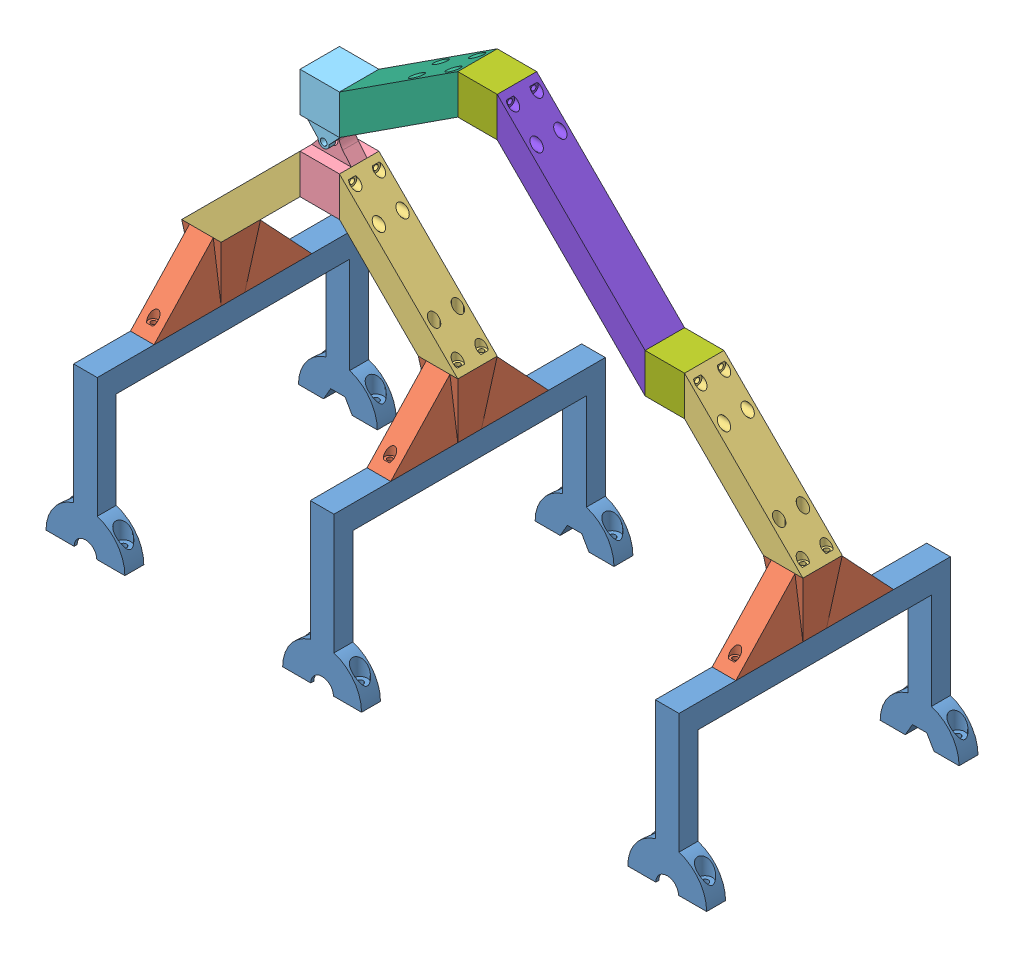
SolidWorks assembly Rocker_Bogie_1.0, configuration Default. Lengths in mm.
Overall size (418.71 308.71 172).
16 component instances, 8 part files, 24 mates.
Components (placement in the parent):
- Rocker_1.0-1: Rocker_1.0 [Default] at (-37.3231 -23.6095 57.3798) size (200 230 172)
  - foot_1.0-1: foot_1.0 [Default] at (23.1128 115.6532 136.1153) size (50 100 172)
  - foot_connect_1.0-1: foot_connect_1.0 [Default] at (23.1128 123.1532 136.1153) x (0 0 -1) z (1 0 0) size (100 40 25)
  - Rocker_Bar_1.0-1: Rocker_Bar_1.0 [Default] at (85.6128 213.1532 123.6153) x (0 0 1) z (-1 0 0) size (25 75 75)
  - Rocker_Pivot_1.0-1: Rocker_Pivot_1.0 [Default] at (98.1128 213.1532 136.1153) size (25 40 25)
  - Rocker_Bar_1.0-2: Rocker_Bar_1.0 [Default] at (160.6128 163.1532 123.6153) x (0 0 1) z (0 1 0) size (25 75 75)
  - foot_connect_1.0-2: foot_connect_1.0 [Default] at (173.1128 123.1532 136.1153) x (0.000001 0 -1) z (1 0 0.000001) size (100 40 25)
  - foot_1.0-2: foot_1.0 [Default] at (173.1128 115.6532 136.1153) x (1 0 0.000001) z (-0.000001 0 1) size (50 100 172)
- Rocker_Bogie_Connect_1.0-1: Rocker_Bogie_Connect_1.0 [Default] at (60.7897 247.0437 193.4951) x (0 1 0) z (1 0 0) size (38.5 25 25)
- Bogie_Bar_1.0-1: Bogie_Bar_1.0 [Default] at (148.2897 283.2492 180.9951) x (0 0 1) z (-1 0 0) size (25 73.71 75)
- Bogie_Connect_1.0-1: Bogie_Connect_1.0 [Default] at (160.7897 283.2492 193.4951) size (25 25 25)
- Bogie_Bar2_1.0-1: Bogie_Bar2_1.0 [Default] at (173.2897 283.2492 205.9951) x (0 0 -1) z (1 0 0) size (25 118.71 93.71)
- Bogie_Connect_1.0-2: Bogie_Connect_1.0 [Default] at (279.4996 189.5393 193.4951) size (25 25 25)
- Rocker_Bar_1.0-1: Rocker_Bar_1.0 [Default] at (291.9996 189.5393 205.9951) x (0 0 -1) z (1 0 0) size (25 75 75)
- foot_connect_1.0-1: foot_connect_1.0 [Default] at (354.4996 99.5393 193.4952) x (0 0 -1) z (1 0 0) size (100 40 25)
- foot_1.0-1: foot_1.0 [Default] at (354.4996 92.0393 193.4952) size (50 100 172)
Mates (geometry in assembly coordinates):
- Concentric1: concentric: cylinder of Rocker_1.0-1/Rocker_Pivot_1.0-1 through (60.7897 224.5437 198.4951) axis (0 0 -1) radius 4; cylinder of Rocker_Bogie_Connect_1.0-1 through (60.7897 224.5437 187.4951) axis (0 0 1) radius 2.5
- Coincident1: coincident: plane of Rocker_1.0-1/Rocker_Pivot_1.0-1 through (48.2897 214.5437 180.9951) normal (0 0 -1); plane of Rocker_Bogie_Connect_1.0-1 through (48.2897 234.5437 180.9951) normal (0 0 -1)
- Coincident3: coincident: plane of Rocker_Bogie_Connect_1.0-1 through (73.2897 247.0437 193.4951) normal (1 0 0); plane of Bogie_Bar_1.0-1 through (73.2897 234.5437 205.9951) normal (-1 0 0)
- Concentric2: concentric: cylinder of Rocker_Bogie_Connect_1.0-1 through (73.2897 239.5437 200.9951) axis (1 0 0) radius 2.5; circle of Bogie_Bar_1.0-1
- Concentric3: concentric: cylinder of Bogie_Bar_1.0-1 through (73.2887 303.2492 200.9951) axis (1 0 0) radius 1.6; cylinder of Bogie_Connect_1.0-1 through (148.2897 303.2492 200.9951) axis (-1 0 0) radius 2.5
- Coincident4: coincident: plane of Bogie_Bar_1.0-1 through (148.2897 283.2492 205.9951) normal (0 0 1); plane of Bogie_Connect_1.0-1 through (148.2897 308.2492 205.9951) normal (0 0 1)
- Coincident5: coincident: plane of Bogie_Bar_1.0-1 through (148.2897 308.2492 205.9951) normal (1 0 0); plane of Bogie_Connect_1.0-1 through (148.2897 308.2492 180.9951) normal (-1 0 0)
- Coincident6: coincident: plane of Rocker_Bogie_Connect_1.0-1 through (48.2897 234.5437 180.9951) normal (0 0 -1); plane of Bogie_Bar_1.0-1 through (148.2897 283.2492 180.9951) normal (0 0 -1)
- Parallel3: parallel: line of Rocker_1.0-1/Rocker_Pivot_1.0-1 through (48.2897 214.5437 205.9951) axis (1 0 0); line of Rocker_Bogie_Connect_1.0-1 through (48.2897 234.5437 205.9951) axis (1 0 0)
- Coincident12: coincident: plane of Bogie_Connect_1.0-1 through (173.2897 308.2492 180.9951) normal (1 0 0); plane of Bogie_Bar2_1.0-1 through (173.2897 308.2492 180.9951) normal (-1 0 0)
- Concentric5: concentric: cylinder of Bogie_Connect_1.0-1 through (173.2897 303.2492 185.9951) axis (1 0 0) radius 2.5; circle of Bogie_Bar2_1.0-1
- Coincident13: coincident: plane of Bogie_Connect_1.0-1 through (148.2897 308.2492 205.9951) normal (0 0 1); plane of Bogie_Bar2_1.0-1 through (173.2897 283.2492 205.9951) normal (0 0 1)
- Coincident14: coincident: plane of Bogie_Bar2_1.0-1 through (266.9996 189.5393 180.9951) normal (1 0 0); plane of Bogie_Connect_1.0-2 through (266.9996 214.5393 180.9951) normal (-1 0 0)
- Coincident15: coincident: plane of Bogie_Bar2_1.0-1 through (173.2897 283.2492 205.9951) normal (0 0 1); plane of Bogie_Connect_1.0-2 through (266.9996 214.5393 205.9951) normal (0 0 1)
- Concentric6: concentric: cylinder of Bogie_Bar2_1.0-1 through (173.2887 209.5393 200.9951) axis (1 0 0) radius 1.6; cylinder of Bogie_Connect_1.0-2 through (266.9996 209.5393 200.9951) axis (-1 0 0) radius 2.5
- Coincident16: coincident: plane of Bogie_Connect_1.0-2 through (266.9996 214.5393 205.9951) normal (0 0 1); plane of Rocker_Bar_1.0-1 through (291.9996 189.5393 205.9951) normal (0 0 1)
- Coincident17: coincident: plane of Bogie_Connect_1.0-2 through (291.9996 214.5393 180.9951) normal (1 0 0); plane of Rocker_Bar_1.0-1 through (291.9996 214.5393 180.9951) normal (-1 0 0)
- Concentric7: concentric: cylinder of Bogie_Connect_1.0-2 through (291.9996 209.5393 185.9951) axis (1 0 0) radius 2.5; circle of Rocker_Bar_1.0-1
- Coincident18: coincident: plane of Rocker_Bar_1.0-1 through (341.9996 139.5393 180.9951) normal (0 -1 0); plane of foot_connect_1.0-1 through (354.4996 139.5393 193.4952) normal (0 1 0)
- Coincident19: coincident: line of Rocker_Bar_1.0-1 through (366.9996 139.5393 180.9951) axis (0 0 1); line of foot_connect_1.0-1 through (366.9996 139.5393 205.9951) axis (0 0 -1)
- Concentric8: concentric: circle of Rocker_Bar_1.0-1; cylinder of foot_connect_1.0-1 through (361.9996 139.5393 200.9951) axis (0 1 0) radius 2.5
- Coincident20: coincident: plane of foot_connect_1.0-1 through (361.9996 184.6087 193.4952) normal (1 0 0); plane of foot_1.0-1 through (361.9996 99.5393 279.4952) normal (1 0 0)
- Concentric9: concentric: cylinder of foot_connect_1.0-1 through (354.4996 139.5393 236.4952) axis (0 -1 0) radius 1.6; cylinder of foot_1.0-1 through (354.4996 99.5393 236.4952) axis (0 1 0) radius 2.5
- Coincident21: coincident: plane of foot_connect_1.0-1 through (354.4996 99.5393 193.4952) normal (0 -1 0); plane of foot_1.0-1 through (346.9996 99.5393 279.4952) normal (0 1 0)
